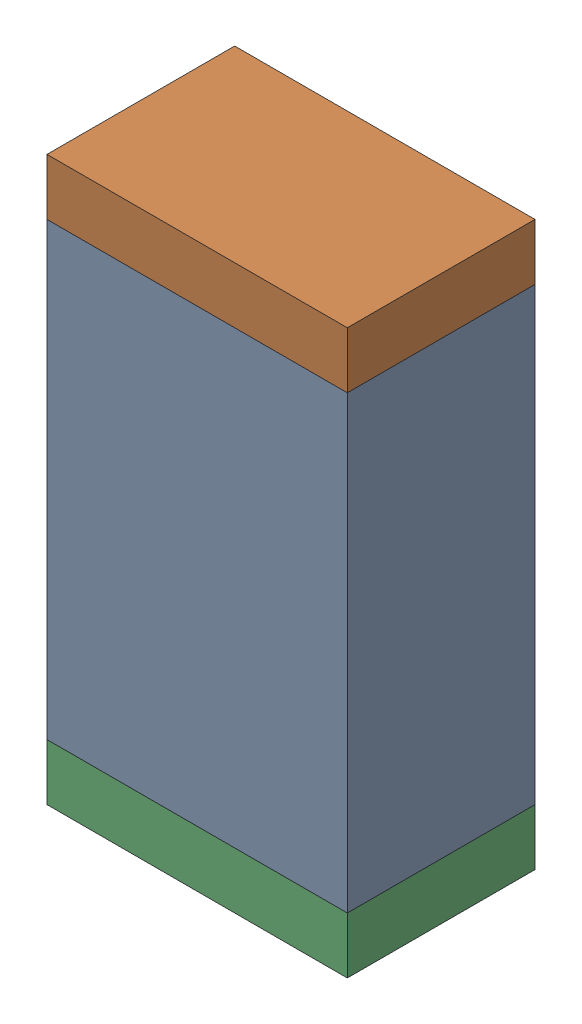
SolidWorks assembly D28, configuration Default. Lengths in mm.
Overall size (0.8 1.5 0.5).
6 component instances, 2 part files, 0 mates.
Components (placement in the parent):
- 810156976-1: 810156976 [Default] at (132.7 63.45 0) size (0.8 1.2 0.5)
  - Extruded_6-1: Extruded_6 [Default] at origin size (0.8 1.2 0.5)
- 810156592-1: 810156592 [Default] at (132.7 64.125 0) size (0.8 0.15 0.5)
  - Extruded_7-1: Extruded_7 [Default] at origin size (0.8 0.15 0.5)
- 810156592-2: 810156592 [Default] at (132.7 62.775 0) size (0.8 0.15 0.5)
  - Extruded_7-1: Extruded_7 [Default] at origin size (0.8 0.15 0.5)
